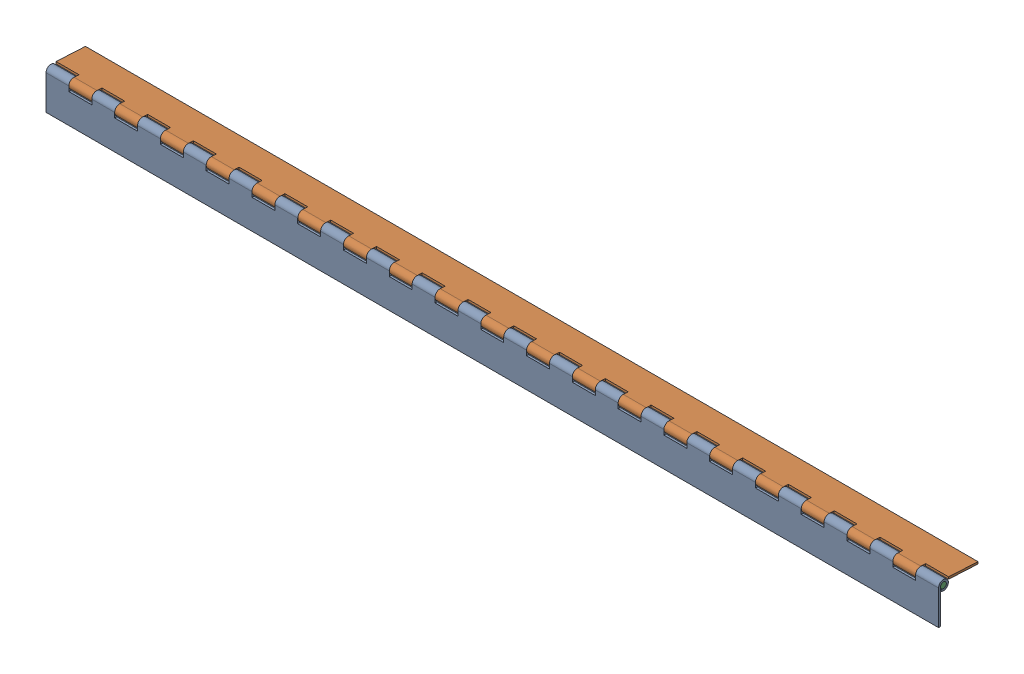
SolidWorks assembly FE-00014-02_ASM, configuration Default. Lengths in mm.
Overall size (990.6 43.84 44.07).
3 component instances, 3 part files, 0 mates.
Components (placement in the parent):
- FE-00014-02-A-1: FE-00014-02-A [Default] at origin size (990.6 43.56 10.92)
- FE-00014-02-B-1: FE-00014-02-B [Default] at (0 5.4535 -5.7468) x (-1 0 0) z (0 0.99863 -0.052336) size (990.6 43.56 10.92)
- FE-00014-02-C-1: FE-00014-02-C [Default] at (0 0 -5.461) size (990.6 6.35 6.35)
